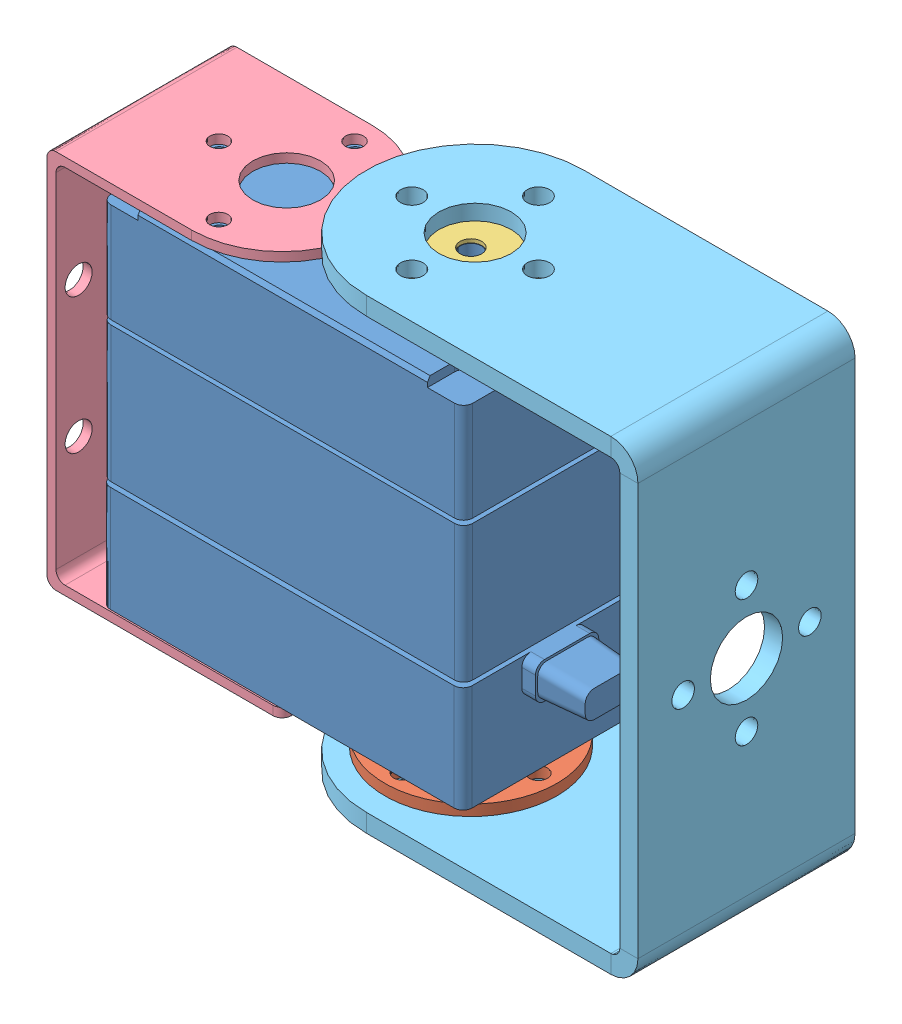
SolidWorks assembly Assem1, configuration Default. Lengths in mm.
Overall size (67.3 51.5 26.87).
5 component instances, 5 part files, 7 mates.
Components (placement in the parent):
- dual shaft servo-1: dual shaft servo [Predeterminado] at (14.992 2.8195 38.2318) size (46.51 48.8 20.07)
- accessory 1-1: accessory 1 [Predeterminado] at (35.7217 1.0691 58.2951) x (0.70399 0 0.71021) z (0.71021 0 -0.70399) size (19 2.2 19)
- accessory 2-2: accessory 2 [Predeterminado] at (7.8921 46.4181 29.4135) x (-0.683613 0 -0.729844) z (0.729844 0 -0.683613) size (19 3.2 19)
- support 1 ( dimensions check)-1: support 1 ( dimensions check) [Predeterminado] at (-9.1537 29.6478 38.798) x (0 1 0) z (0 0 -1) size (42 26 20)
- U Bracket-1: U Bracket [Défaut] at (58.1419 23.5615 38.2647) x (0 -1 0) z (0 0 -1) size (51.5 42 24)
Mates (geometry in assembly coordinates):
- Concentric14: concentric anti-aligned: circle of dual shaft servo-1; circle of accessory 1-1
- Concentric16: concentric aligned: circle of dual shaft servo-1; circle of accessory 2-2
- Parallel6: parallel anti-aligned: plane of dual shaft servo-1 through (-3.158 30.3195 28.2318) normal (-1 0 0); plane of support 1 ( dimensions check)-1 through (-8.1537 29.6478 38.798) normal (1 0 0)
- Concentric21: concentric anti-aligned: circle of dual shaft servo-1; circle of support 1 ( dimensions check)-1
- Concentric22: concentric anti-aligned: circle of dual shaft servo-1; circle of support 1 ( dimensions check)-1
- Parallel7: parallel anti-aligned: plane of dual shaft servo-1 through (36.842 30.3195 38.2318) normal (1 0 0); plane of U Bracket-1 through (56.1419 49.3115 26.2647) normal (-1 0 0)
- Concentric24: concentric anti-aligned: circle of accessory 1-1; circle of U Bracket-1
